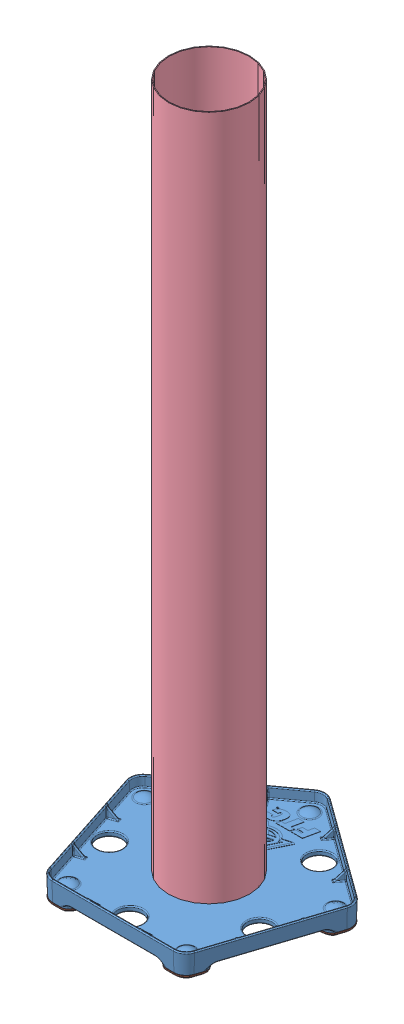
SolidWorks assembly Rolling Goal 90, configuration Default. Lengths in mm.
Overall size (291.98 900.58 285.9).
12 component instances, 4 part files, 0 mates.
Components (placement in the parent):
- Rolling Goal Base-1: Rolling Goal Base [Default] at (-9.8868 20.1576 -8.4777) size (283.35 51.39 274.75)
- Rolling Goal Caster Mount-1: Rolling Goal Caster Mount [Default] at (-84.6377 13.8076 94.5082) x (0.809017 0 -0.587785) z (0.587785 0 0.809017) size (40.81 17.65 43.23)
- Rolling Goal Caster-1: Rolling Goal Caster [Default] at (-85.3501 20.1576 95.3886) size (25.4 25.4 25.4)
- Rolling Goal Caster Mount-2: Rolling Goal Caster Mount [Default] at (64.9593 13.8076 94.439) x (-0.309017 0 -0.951057) z (0.951057 0 -0.309017) size (40.81 17.65 43.23)
- Rolling Goal Caster Mount-3: Rolling Goal Caster Mount [Default] at (111.1214 13.8076 -47.8575) x (-1 0 0) z (0 0 -1) size (40.81 17.65 43.23)
- Rolling Goal Caster Mount-4: Rolling Goal Caster Mount [Default] at (-9.9457 13.8076 -135.7324) x (-0.309017 0 0.951057) z (-0.951057 0 -0.309017) size (40.81 17.65 43.23)
- Rolling Goal Caster Mount-5: Rolling Goal Caster Mount [Default] at (-130.9315 13.8076 -47.7455) x (0.809017 0 0.587785) z (-0.587785 0 0.809017) size (40.81 17.65 43.23)
- Rolling Goal Caster-2: Rolling Goal Caster [Default] at (65.5764 20.1576 95.3886) x (0.309017 0 -0.951057) z (0.951057 0 0.309017) size (25.4 25.4 25.4)
- Rolling Goal Caster-3: Rolling Goal Caster [Default] at (112.2152 20.1576 -48.151) x (-0.809017 0 -0.587785) z (0.587785 0 -0.809017) size (25.4 25.4 25.4)
- Rolling Goal Caster-4: Rolling Goal Caster [Default] at (-9.8868 20.1576 -136.8634) x (-0.809017 0 0.587785) z (-0.587785 0 -0.809017) size (25.4 25.4 25.4)
- Rolling Goal Caster-5: Rolling Goal Caster [Default] at (-131.9889 20.1576 -48.151) x (0.309017 0 0.951057) z (-0.951057 0 0.309017) size (25.4 25.4 25.4)
- Rolling Goal 90 Pipe-1: Rolling Goal 90 Pipe [Default] at (-9.8868 32.8576 -8.4777) size (103.63 874.6 103.63)
